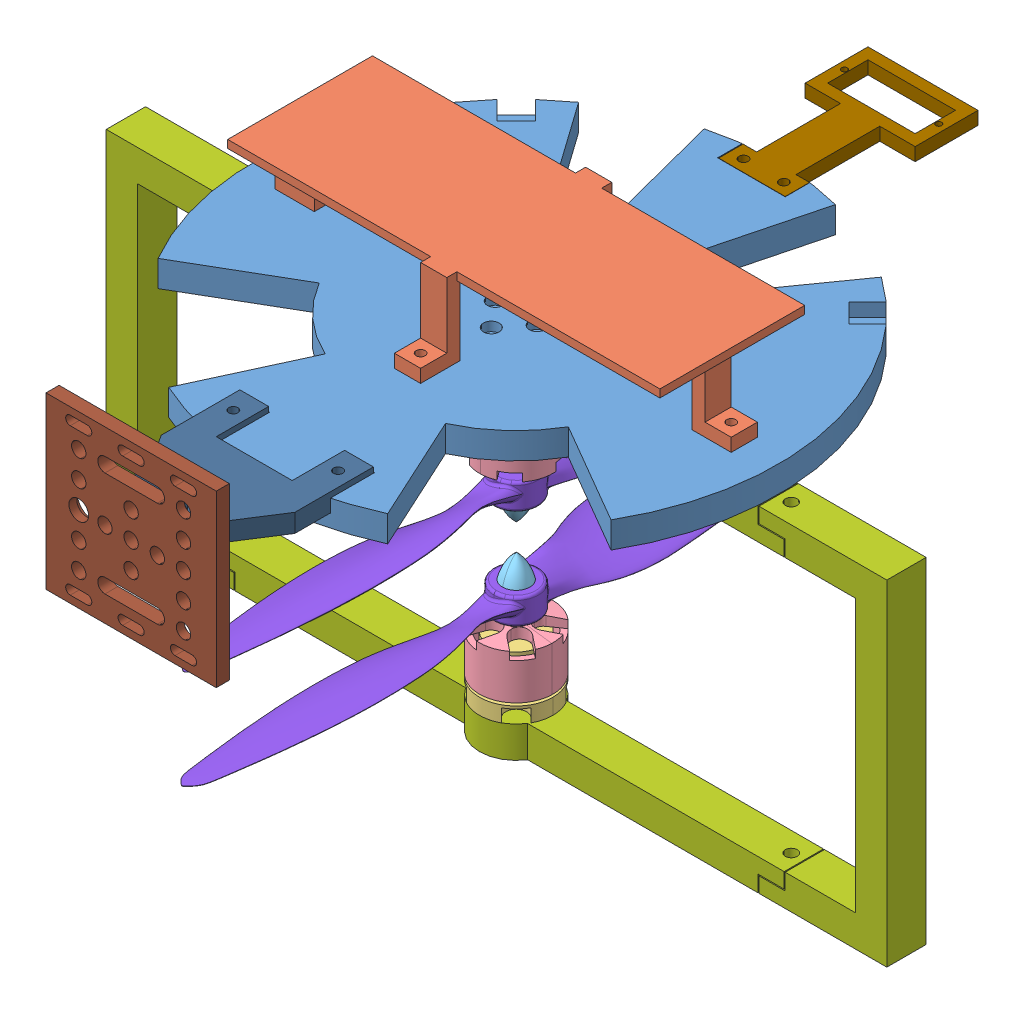
SolidWorks assembly test_stand, configuration Default. Lengths in mm.
Overall size (298 168.9 302.3).
18 component instances, 11 part files, 29 mates.
Components (placement in the parent):
- test_frame-1: test_frame [Default] at (80.1927 98.2545 151.3533) size (200 10 200)
- second_frame-1: second_frame [Default] at (80.1927 108.2545 151.3533) x (1 0 0) z (0 1 0) size (174.17 83 30)
- User Library-emaxmodel-mt2213.STEP-1: User Library-emaxmodel-mt2213.STEP [Default] at (80.1927 86.2545 151.3533) x (1 0 0) z (0 0 -1) size (36.98 47 36.98)
  - emaxmodel-mt2213-stator_По умолчанию.STEP-1: emaxmodel-mt2213-stator_По умолчанию.STEP [Default] at origin size (28 21 28)
  - emaxmodel-mt2213-rotor_По умолчанию.STEP-1: emaxmodel-mt2213-rotor_По умолчанию.STEP [Default] at (0 7 0) x (0.999557 0 0.02976) z (-0.02976 0 0.999557) size (28 32 28)
  - emaxmodel-mt2213-cone_По умолчанию.STEP-1: emaxmodel-mt2213-cone_По умолчанию.STEP [Default] at (0 32 0) size (12 15 13.86)
  - wires_По умолчанию.STEP-1: wires_По умолчанию.STEP [Default] at (-15.8508 1.5 15.8508) x (0.707107 0 0.707107) z (-0.707107 0 0.707107) size (7 3 19)
- motor_mount_bottom-1: motor_mount_bottom [Default] at (80.1927 98.2545 151.3533) x (-1 0 0) z (0 -1 0) size (298 28 128)
- Propeller 10x45.step-1: Propeller 10x45.step [Default] at (80.1927 53.2545 151.3533) size (28.85 11.2 254.24)
- User Library-emaxmodel-mt2213.STEP-2: User Library-emaxmodel-mt2213.STEP [Default] at (80.1927 -17.7455 151.3533) x (0 0 1) z (-1 0 0) size (36.98 47 36.98)
  - emaxmodel-mt2213-stator_По умолчанию.STEP-1: emaxmodel-mt2213-stator_По умолчанию.STEP [Default] at origin size (28 21 28)
  - emaxmodel-mt2213-rotor_По умолчанию.STEP-1: emaxmodel-mt2213-rotor_По умолчанию.STEP [Default] at (0 7 0) x (0.999557 0 0.02976) z (-0.02976 0 0.999557) size (28 32 28)
  - emaxmodel-mt2213-cone_По умолчанию.STEP-1: emaxmodel-mt2213-cone_По умолчанию.STEP [Default] at (0 32 0) size (12 15 13.86)
  - wires_По умолчанию.STEP-1: wires_По умолчанию.STEP [Default] at (-15.8508 1.5 15.8508) x (0.707107 0 0.707107) z (-0.707107 0 0.707107) size (7 3 19)
- Propeller 10x45.step-4: Propeller 10x45.step [Default] at (80.1927 15.2545 151.3533) x (-0.999997 0 -0.002493) z (-0.002493 0 0.999997) size (28.85 11.2 254.24)
- LIDAR Sensor Mount For V1.1-1: LIDAR Sensor Mount For V1.1 [Default] at (59.1927 103.1545 20.0533) size (42 5 65.3)
- Slide Mount-1: Slide Mount [Default] at (54.6927 103.1545 293.3533) size (51 27 62)
- Slider Plate-1: Slider Plate [Default] at (112.6927 74.1545 298.3533) x (-1 0 0) z (0 -1 0) size (65 5 65)
Mates (geometry in assembly coordinates):
- InPlace1: in place: plane of test_frame-1 through (80.1927 108.2545 151.3533) normal (0 1 0); plane of ? through (0 108.2545 0) normal (0 1 0); moOrthogonalPlaneRef_w of test_frame-1 through (80.1927 108.2545 151.3533) normal (0 1 0); plane of ? through (0 108.2545 0) normal (0 0 -1); plane of test_frame-1 through (80.1927 108.2545 151.3533) normal (0 1 0); plane of ? through (0 108.2545 0) normal (1 0 0); plane of test_frame-1 through (80.1927 108.2545 151.3533) normal (0 1 0); unknown of second_frame-1
- Coincident1: coincident aligned: plane of test_frame-1; plane of second_frame-1
- Coincident2: coincident aligned: moOrthogonalPlaneRef_w of test_frame-1 through (80.1927 108.2545 151.3533) normal (0 0 -1); plane of Part2^Assem1-1 through (80.1927 108.2545 151.3533) normal (0 0 -1)
- Coincident3: coincident anti-aligned: moOrthogonalPlaneRef_w of test_frame-1 through (80.1927 108.2545 151.3533) normal (-1 0 0); plane of Part2^Assem1-1 through (80.1927 108.2545 151.3533) normal (1 0 0)
- Parallel1: parallel anti-aligned: plane of test_frame-1 through (80.1927 98.2545 151.3533) normal (0 -1 0); plane of motor_mount_bottom-1 through (80.1927 98.2545 151.3533) normal (0 1 0)
- Concentric1: concentric anti-aligned: cylinder of test_frame-1 through (80.1927 108.2545 151.3533) axis (0 -1 0) radius 100; cylinder of User Library-emaxmodel-mt2213.STEP-1/emaxmodel-mt2213-rotor_По умолчанию.STEP-1 through (80.1927 65.2545 151.3533) axis (0 1 0) radius 14
- Distance1: distance = 12 mm anti-aligned: plane of test_frame-1 through (80.1927 98.2545 151.3533) normal (0 -1 0); plane of User Library-emaxmodel-mt2213.STEP-1/emaxmodel-mt2213-stator_По умолчанию.STEP-1 through (80.1927 86.2545 151.3533) normal (0 1 0)
- InPlace2: in place: plane of test_frame-1 through (80.1927 98.2545 151.3533) normal (0 -1 0); plane of ? through (0 98.2545 0) normal (0 -1 0); plane of test_frame-1 through (80.1927 98.2545 151.3533) normal (0 -1 0); plane of ? through (0 98.2545 0) normal (0 0 -1); plane of test_frame-1 through (80.1927 98.2545 151.3533) normal (0 -1 0); plane of ? through (0 98.2545 0) normal (-1 0 0); plane of test_frame-1 through (80.1927 98.2545 151.3533) normal (0 -1 0); unknown of motor_mount_bottom-1
- Coincident6: coincident aligned: plane of test_frame-1; plane of motor_mount_bottom-1
- Coincident7: coincident aligned: moOrthogonalPlaneRef_w of test_frame-1 through (80.1927 98.2545 151.3533) normal (0 0 -1); plane of motor_mount_bottom-1 through (80.1927 98.2545 151.3533) normal (0 0 -1)
- Coincident8: coincident anti-aligned: moOrthogonalPlaneRef_w of test_frame-1 through (80.1927 98.2545 151.3533) normal (1 0 0); plane of motor_mount_bottom-1 through (80.1927 98.2545 151.3533) normal (-1 0 0)
- Concentric2: concentric aligned: cylinder of Propeller 10x45.step-1 through (80.1927 48.2545 151.3533) axis (0 1 0) radius 3; cylinder of User Library-emaxmodel-mt2213.STEP-1/emaxmodel-mt2213-rotor_По умолчанию.STEP-1 through (80.1927 47.2545 151.3533) axis (0 1 0) radius 3
- Coincident9: coincident anti-aligned: plane of Propeller 10x45.step-1 through (80.1927 58.2545 151.3533) normal (0 1 0); plane of User Library-emaxmodel-mt2213.STEP-1/emaxmodel-mt2213-rotor_По умолчанию.STEP-1 through (80.1927 58.2545 151.3533) normal (0 -1 0)
- Parallel7: parallel aligned: plane of motor_mount_bottom-1 through (80.1927 86.2545 151.3533) normal (0 -1 0); plane of User Library-emaxmodel-mt2213.STEP-2/emaxmodel-mt2213-stator_По умолчанию.STEP-1 through (80.1927 -17.7455 151.3533) normal (0 -1 0)
- Concentric11: concentric anti-aligned: cylinder of User Library-emaxmodel-mt2213.STEP-2/emaxmodel-mt2213-rotor_По умолчанию.STEP-1 through (80.1927 3.2545 151.3533) axis (0 -1 0) radius 14; cylinder of motor_mount_bottom-1 through (80.1927 -69.3435 151.3533) axis (0 1 0) radius 14
- Parallel8: parallel aligned: line of User Library-emaxmodel-mt2213.STEP-2/wires_По умолчанию.STEP-1 through (70.3523 -16.2455 146.4626) axis (-0.707107 0 -0.707107); line of User Library-emaxmodel-mt2213.STEP-1/wires_По умолчанию.STEP-1 through (75.302 84.7545 141.5129) axis (-0.707107 0 -0.707107)
- Distance2: distance = 104 mm aligned: plane of User Library-emaxmodel-mt2213.STEP-2/emaxmodel-mt2213-stator_По умолчанию.STEP-1 through (80.1927 -17.7455 151.3533) normal (0 -1 0); plane of motor_mount_bottom-1 through (80.1927 86.2545 151.3533) normal (0 -1 0)
- Coincident31: coincident anti-aligned: plane of Propeller 10x45.step-4 through (80.1927 10.2545 151.3533) normal (0 -1 0); plane of User Library-emaxmodel-mt2213.STEP-2/emaxmodel-mt2213-rotor_По умолчанию.STEP-1 through (80.1927 10.2545 151.3533) normal (0 1 0)
- Concentric12: concentric aligned: cylinder of Propeller 10x45.step-4 through (80.1927 20.2545 151.3533) axis (0 -1 0) radius 3; cylinder of User Library-emaxmodel-mt2213.STEP-2/emaxmodel-mt2213-rotor_По умолчанию.STEP-1 through (80.1927 21.2545 151.3533) axis (0 -1 0) radius 3
- Angle1: planar angle = 5.497787 rad aligned: line of User Library-emaxmodel-mt2213.STEP-1/wires_По умолчанию.STEP-1 through (75.302 84.7545 141.5129) axis (-0.707107 0 -0.707107); line of motor_mount_bottom-1 through (217.1927 86.2545 158.8533) axis (-1 0 0)
- Coincident35: coincident anti-aligned: plane of test_frame-1 through (80.1927 103.1545 151.3533) normal (0 1 0); plane of LIDAR Sensor Mount For V1.1-1 through (59.1927 103.1545 20.0533) normal (0 -1 0)
- Width1: width aligned: plane of LIDAR Sensor Mount For V1.1-1 through (92.8927 76.1054 52.0533) normal (1 0 0); plane of LIDAR Sensor Mount For V1.1-1 through (67.4927 76.1054 52.0533) normal (-1 0 0); plane of test_frame-1 through (67.2927 103.1545 52.1888) normal (1 0 0); plane of test_frame-1 through (93.0927 103.1545 61.5533) normal (-1 0 0)
- Concentric13: concentric aligned: cylinder of test_frame-1 through (72.4927 98.2545 56.871) axis (0 1 0) radius 1.75; cylinder of LIDAR Sensor Mount For V1.1-1 through (72.4927 103.1545 56.871) axis (0 1 0) radius 1.75
- Coincident36: coincident: plane of test_frame-1 through (80.1927 103.1545 151.3533) normal (0 1 0); plane of Slide Mount-1 through (54.6927 103.1545 293.3533) normal (0 -1 0)
- Concentric14: concentric: cylinder of test_frame-1 through (60.1927 98.2545 239.3533) axis (0 1 0) radius 2.75; cylinder of Slide Mount-1 through (60.1927 103.1545 239.3533) axis (0 1 0) radius 1.75
- Concentric15: concentric aligned: cylinder of test_frame-1 through (100.1927 98.2545 239.3533) axis (0 1 0) radius 2.75; cylinder of Slide Mount-1 through (100.1927 103.1545 239.3533) axis (0 1 0) radius 1.75
- Concentric16: concentric: cylinder of Slide Mount-1 through (80.1927 116.6545 231.3533) axis (0 0 1) radius 1.75; cylinder of Slider Plate-1 through (80.1927 116.6545 314.4339) axis (0 0 1) radius 2.75
- Concentric17: concentric: cylinder of Slide Mount-1 through (80.1927 96.6545 231.3533) axis (0 0 1) radius 1.75; cylinder of Slider Plate-1 through (80.1927 96.6545 314.4339) axis (0 0 1) radius 2.75
- Coincident37: coincident anti-aligned: plane of Slide Mount-1 through (54.6927 110.1545 293.3533) normal (0 0 1); plane of Slider Plate-1 through (112.6927 74.1545 293.3533) normal (0 0 -1)
